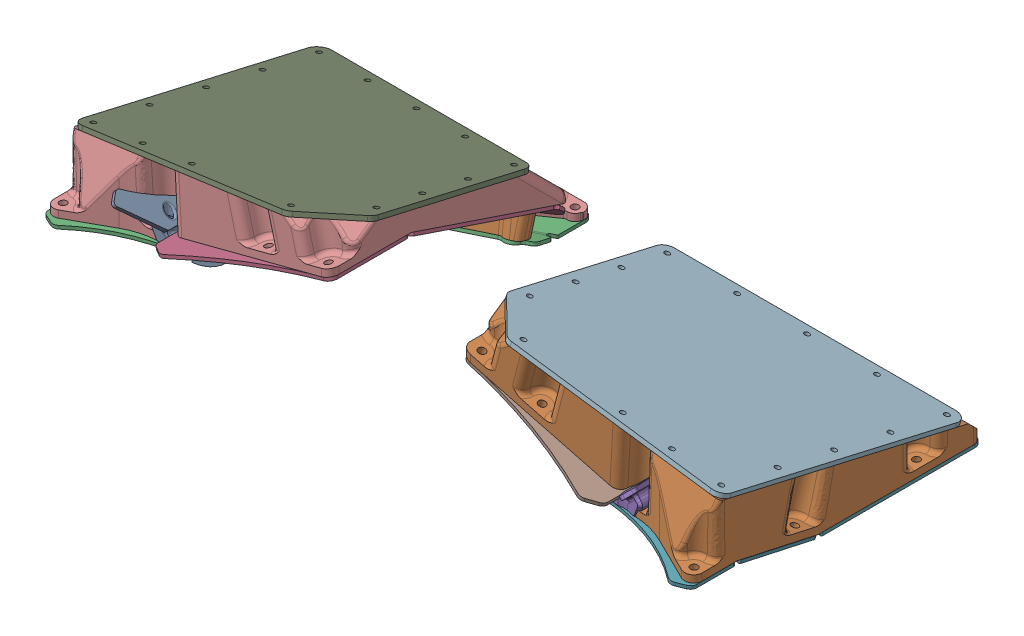
SolidWorks assembly CopeCage_30_v1, configuration Default. Lengths in mm.
Overall size (464.39 82.15 212.73).
2 component instances, 2 part files, 6 mates.
Components (placement in the parent):
- TopPlate2_30_v1-1: TopPlate2_30_v1 [Default] at origin size (464.03 56.19 211.86)
- CopeCushion_30_v1-1: CopeCushion_30_v1 [Default] at origin size (464.39 79.86 207.65)
Mates (geometry in assembly coordinates):
- Coincident1: coordinate: point of TopPlate2_30_v1-1
- Coincident2: coincident aligned: plane of TopPlate2_30_v1-4 through (0 28.3558 21.8498) normal (1 0 0)
- Coincident4: coincident: line of TopPlate2_30_v1-4 through (226.695 43.7803 -9.8858) axis (-1 0 0)
- Distance1: distance = 20.828 mm: plane of TopPlate2_30_v1-1 through (0 20.701 0) normal (0 1 0); line of TopPlate2_30_v1-4 through (226.695 41.529 -9.4888) axis (-1 0 0)
- Angle1: planar angle = 0.174533 rad anti-aligned: plane of TopPlate2_30_v1-1 through (0 20.701 0) normal (0 1 0); plane of TopPlate2_30_v1-4 through (0 46.491 18.6521) normal (0 -0.984808 0.173648)
- Coincident7: coordinate: unknown of CopeCushion_30_v1-1
